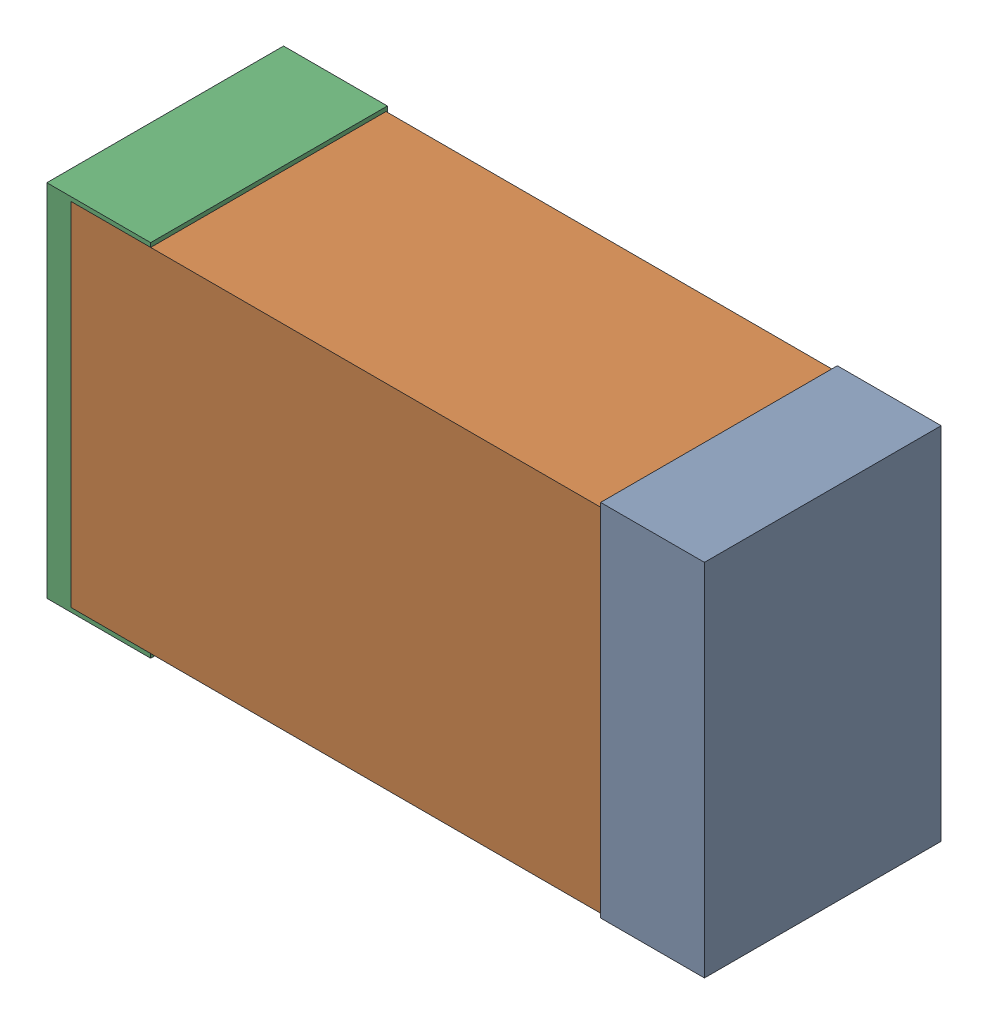
SolidWorks assembly USB23_FB3, configuration Default. Lengths in mm.
Overall size (2.38 1.3 0.85).
6 component instances, 2 part files, 0 mates.
Components (placement in the parent):
- 384311232-1: 384311232 [Default] at (163.814 54.229 -1.9574) size (0.38 1.3 0.85)
  - Extruded_8-1: Extruded_8 [Default] at origin size (0.38 1.3 0.85)
- 402662800-1: 402662800 [Default] at (162.814 54.229 -1.9524) size (2.2 1.27 0.85)
  - Extruded_30-1: Extruded_30 [Default] at origin size (2.2 1.27 0.85)
- 384311232-2: 384311232 [Default] at (161.814 54.229 -1.9574) size (0.38 1.3 0.85)
  - Extruded_8-1: Extruded_8 [Default] at origin size (0.38 1.3 0.85)
